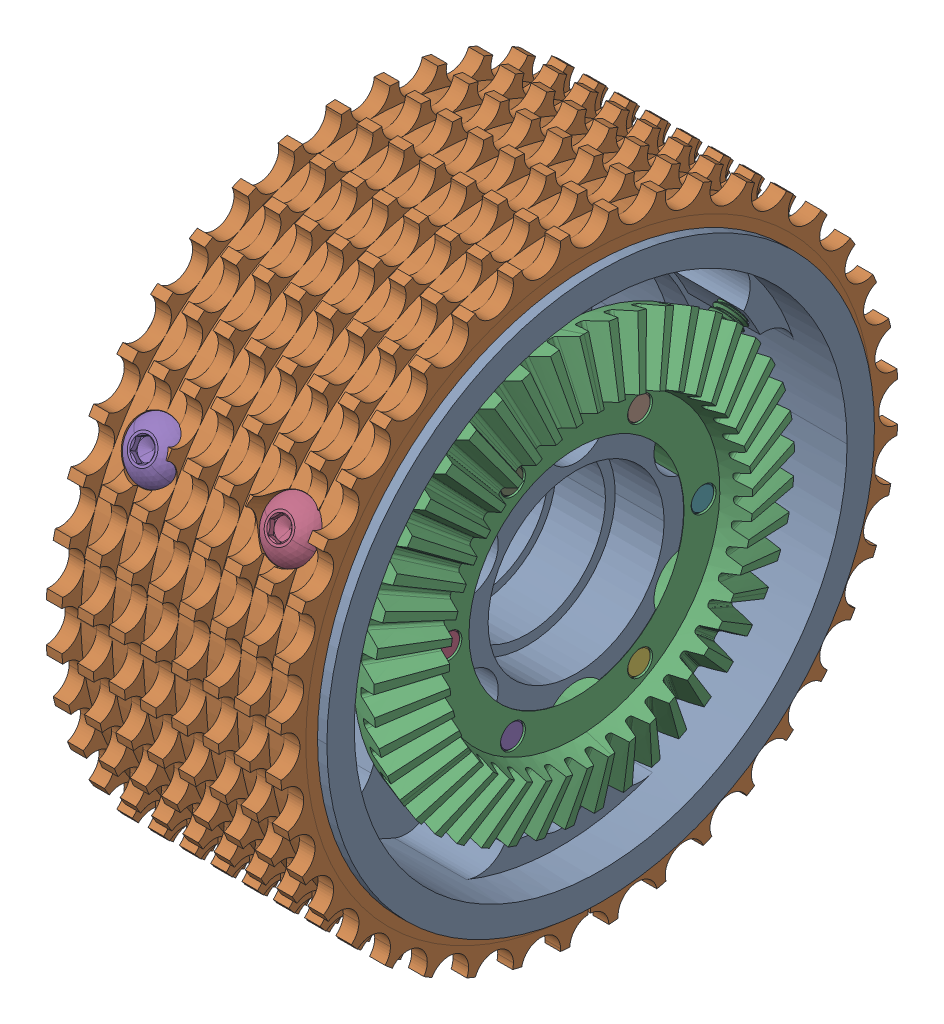
SolidWorks assembly MK4 Billet Wheel Assembly.STEP, configuration Default. Lengths in mm.
Overall size (42.38 100.13 100.13).
17 component instances, 5 part files, 0 mates.
Components (placement in the parent):
- Wheel, SDS, Nitrile Tread, 4in X 1.5in, Bearing Bore.STEP-1: Wheel, SDS, Nitrile Tread, 4in X 1.5in, Bearing Bore.STEP [Default] at origin size (42.28 88.9 88.9)
- Tread, Blue Nitrile 4in X 1.5in.STEP-1: Tread, Blue Nitrile 4in X 1.5in.STEP [Default] at origin size (38.1 100.13 100.13)
- Bevel Gear, 4515.STEP-1: Bevel Gear, 4515.STEP [Default] at (16.8297 0 0) x (0 -1 0) z (0 0 1) size (68.38 7.77 68.42)
- Screw, 10-32 X .75, Button, 91255A269_91255A269.STEP-1: Screw, 10-32 X .75, Button, 91255A269_91255A269.STEP [Default] at (-4.826 0 20.6375) x (0 -0.847203 -0.531269) z (-1 0 0) size (9.17 9.17 21.62)
- Screw, 10-32 X .75, Button, 91255A269_91255A269.STEP-2: Screw, 10-32 X .75, Button, 91255A269_91255A269.STEP [Default] at (-4.826 -17.8726 10.3187) x (0 -0.99925 -0.038711) z (-1 0 0) size (9.17 9.17 21.62)
- Screw, 10-32 X .75, Button, 91255A269_91255A269.STEP-3: Screw, 10-32 X .75, Button, 91255A269_91255A269.STEP [Default] at (-4.826 -17.8726 -10.3187) x (0 -0.986188 -0.165633) z (-1 0 0) size (9.17 9.17 21.62)
- Screw, 10-32 X .75, Button, 91255A269_91255A269.STEP-4: Screw, 10-32 X .75, Button, 91255A269_91255A269.STEP [Default] at (-4.826 0 -20.6375) x (0 -0.966455 -0.256836) z (-1 0 0) size (9.17 9.17 21.62)
- Screw, 10-32 X .75, Button, 91255A269_91255A269.STEP-5: Screw, 10-32 X .75, Button, 91255A269_91255A269.STEP [Default] at (-4.826 17.8726 -10.3187) x (0 -0.95104 -0.309068) z (-1 0 0) size (9.17 9.17 21.62)
- Screw, 10-32 X .75, Button, 91255A269_91255A269.STEP-6: Screw, 10-32 X .75, Button, 91255A269_91255A269.STEP [Default] at (-4.826 17.8726 10.3187) x (0 -0.947988 -0.318305) z (-1 0 0) size (9.17 9.17 21.62)
- Screw, 10-32 X .5, Button, 97763A232_97763A232.STEP-1: Screw, 10-32 X .5, Button, 97763A232_97763A232.STEP [Default] at (11.1125 -40.6604 7.1695) x (-0.785325 0.107503 0.609678) z (0 -0.984808 0.173648) size (9.17 9.17 15.27)
- Screw, 10-32 X .5, Button, 97763A232_97763A232.STEP-2: Screw, 10-32 X .5, Button, 97763A232_97763A232.STEP [Default] at (-11.1125 -40.6604 7.1695) x (-0.636812 0.133886 0.759306) z (0 -0.984808 0.173648) size (9.17 9.17 15.27)
- Screw, 10-32 X .5, Button, 97763A232_97763A232.STEP-3: Screw, 10-32 X .5, Button, 97763A232_97763A232.STEP [Default] at (-11.1125 -40.6604 -7.1695) x (0.726076 -0.119403 0.677168) z (0 -0.984808 -0.173648) size (9.17 9.17 15.27)
- Screw, 10-32 X .5, Button, 97763A232_97763A232.STEP-4: Screw, 10-32 X .5, Button, 97763A232_97763A232.STEP [Default] at (11.1125 -40.6604 -7.1695) x (0.841108 -0.09392 0.53265) z (0 -0.984808 -0.173648) size (9.17 9.17 15.27)
- Screw, 10-32 X .5, Button, 97763A232_97763A232.STEP-5: Screw, 10-32 X .5, Button, 97763A232_97763A232.STEP [Default] at (-11.1125 20.6438 -35.7562) x (0.804058 -0.514897 -0.297276) z (0 0.5 -0.866025) size (9.17 9.17 15.27)
- Screw, 10-32 X .5, Button, 97763A232_97763A232.STEP-6: Screw, 10-32 X .5, Button, 97763A232_97763A232.STEP [Default] at (11.1125 20.6438 -35.7562) x (0.926716 -0.32542 -0.187881) z (0 0.5 -0.866025) size (9.17 9.17 15.27)
- Screw, 10-32 X .5, Button, 97763A232_97763A232.STEP-7: Screw, 10-32 X .5, Button, 97763A232_97763A232.STEP [Default] at (11.1125 20.6438 35.7562) x (0.200031 0.848523 -0.489895) z (0 0.5 0.866025) size (9.17 9.17 15.27)
- Screw, 10-32 X .5, Button, 97763A232_97763A232.STEP-8: Screw, 10-32 X .5, Button, 97763A232_97763A232.STEP [Default] at (-11.1125 20.6438 35.7562) x (0.515054 0.74232 -0.428579) z (0 0.5 0.866025) size (9.17 9.17 15.27)
